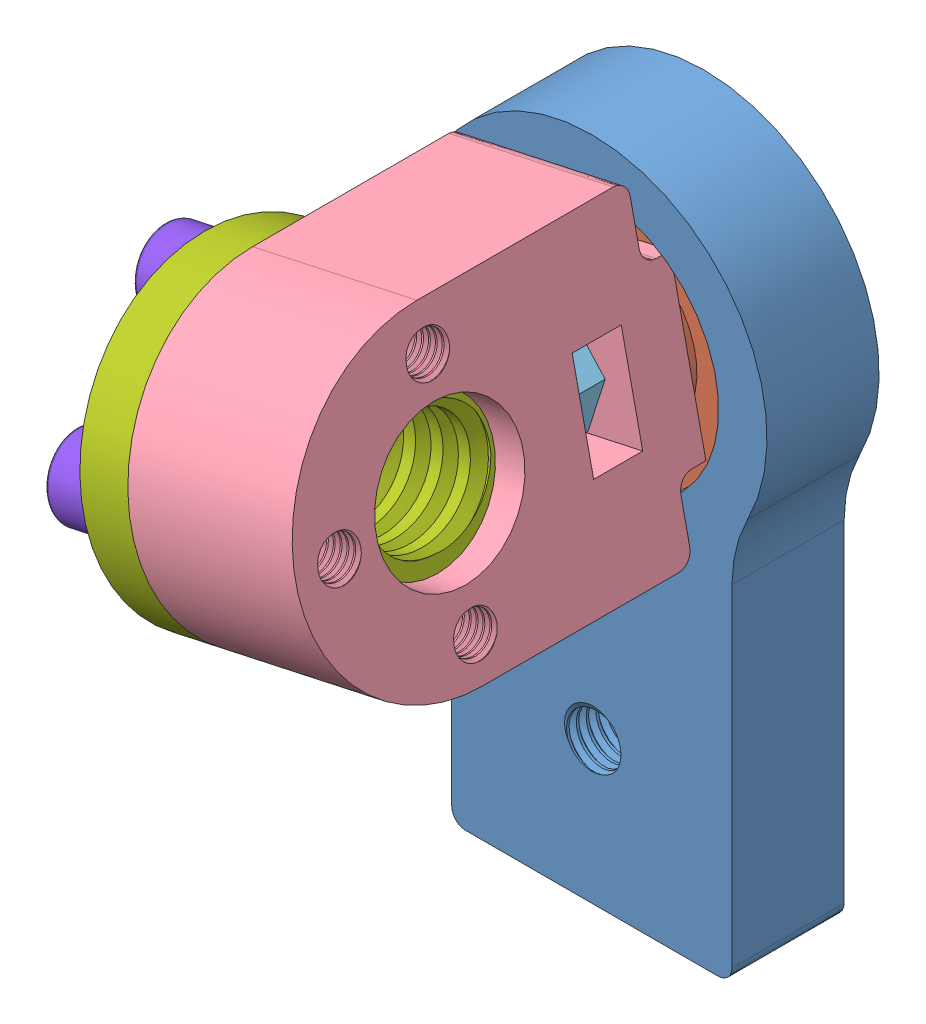
SolidWorks assembly ASM_poignee, configuration Défaut. Lengths in mm.
Overall size (28.85 49.13 41.76).
10 component instances, 8 part files, 25 mates.
Components (placement in the parent):
- fix_poignee_2-1: fix_poignee_2 [Défaut] at (-14.1041 -22.9722 47.5) size (25 47.5 8.25)
- roulement-1: roulement [Défaut] at (-14.1041 12.0278 51) x (0 0 1) z (0.937826 0.347107 0) size (7 22 22)
- rondelle_2-2: rondelle_2 [Défaut] at (-14.1041 12.0278 45.5) x (-0.1266 0.991954 0) z (0 0 -1) size (12.2 12.2 12)
- fix_ecrou_2-2: fix_ecrou_2 [Défaut] at (-8.2412 13.3032 56.5) x (0.212572 -0.977145 0) z (-0.977145 -0.212572 0) size (22 28 12.23)
- ecrou_M4-1: ecrou_M4 [Défaut] at (-14.1041 12.0278 58.5) x (0.672666 -0.739946 0) z (0 0 1) size (8.08 7 3.43)
- M4_16-1: M4_16 [Défaut] at (-14.1041 12.0278 41.5) x (-0.952519 0.30448 0) z (0.30448 0.952519 0) size (7 20.06 7)
- ecrou_cuivre-1: ecrou_cuivre [Défaut] at (-24.8527 9.6895 71.5) x (0.212572 -0.977145 0) z (0 0 1) size (22 16.12 22)
- M3_10-1: M3_10 [Défaut] at (-26.3184 9.3706 79.5) x (0.184093 -0.846233 -0.5) z (0.106286 -0.488573 0.866025) size (5.5 13 5.5)
- M3_10-2: M3_10 [Défaut] at (-28.019 17.1878 71.5) x (0.184093 -0.846233 -0.5) z (0.106286 -0.488573 0.866025) size (5.5 13 5.5)
- M3_10-3: M3_10 [Défaut] at (-24.6178 1.5535 71.5) x (0.184093 -0.846233 -0.5) z (0.106286 -0.488573 0.866025) size (5.5 13 5.5)
Mates (geometry in assembly coordinates):
- Coaxiale1: concentric anti-aligned: cylinder of fix_poignee_2-1 through (-14.1041 12.0278 54.5) axis (0 0 -1) radius 11.05; cylinder of roulement-1 through (-14.1041 12.0278 51) axis (0 0 1) radius 11
- Coïncidente1: coincident anti-aligned: plane of fix_poignee_2-1 through (-14.1041 12.0278 54.5) normal (0 0 -1); plane of roulement-1 through (-10.4594 2.1806 54.5) normal (0 0 1)
- Coaxiale4: concentric aligned: cylinder of roulement-1 through (-14.1041 12.0278 51) axis (0 0 1) radius 4; cylinder of rondelle_2-2 through (-14.1041 12.0278 53.0974) axis (0 0 1) radius 4.1
- Coïncidente5: coincident anti-aligned: plane of roulement-1 through (-12.5421 7.8076 47.5) normal (0 0 -1); plane of rondelle_2-2 through (-13.3318 5.9769 47.5) normal (0 0 1)
- Coaxiale5: concentric anti-aligned: cylinder of rondelle_2-2 through (-14.1041 12.0278 53.0974) axis (0 0 1) radius 4.1; cylinder of fix_ecrou_2-2 through (-14.1041 12.0278 63.5) axis (0 0 -1) radius 2.5
- Coïncidente6: coincident anti-aligned: plane of rondelle_2-2 through (-11.5953 15.2706 57.5) normal (0.790937 -0.611898 0); plane of fix_ecrou_2-2 through (-11.5035 15.3893 65.6544) normal (-0.790937 0.611898 0)
- Coïncidente7: coincident anti-aligned: plane of roulement-1 through (-12.0214 6.4008 54.5) normal (0 0 1); plane of fix_ecrou_2-2 through (-21.2424 16.6152 54.5) normal (0 0 -1)
- Coaxiale6: concentric aligned: cylinder of fix_ecrou_2-2 through (-14.1041 12.0278 63.5) axis (0 0 -1) radius 2.5; cone of ecrou_M4-1 through (-14.1041 12.0278 61.2) axis (0 0 -1)
- Coïncidente8: coincident anti-aligned: plane of fix_ecrou_2-2 through (-20.7322 14.2701 58.5) normal (0 0 1); plane of ecrou_M4-1 through (-14.1041 12.0278 58.5) normal (0 0 -1)
- Parallèle1: parallel anti-aligned: plane of fix_ecrou_2-2 through (-19.2017 7.2346 62) normal (-0.212572 0.977145 0); plane of ecrou_M4-1 through (-15.3346 8.1782 61.7) normal (0.212572 -0.977145 0)
- Coaxiale7: concentric aligned: cylinder of rondelle_2-2 through (-14.1041 12.0278 53.0974) axis (0 0 1) radius 2.5; cylinder of M4_16-1 through (-14.1041 12.0278 61.5) axis (0 0 1) radius 3.5
- Coïncidente10: coincident anti-aligned: plane of rondelle_2-2 through (-13.7876 9.5479 45.5) normal (0 0 -1); plane of M4_16-1 through (-10.7703 10.9621 45.5) normal (0 0 1)
- Parallèle3: parallel aligned: plane of fix_ecrou_2-2 through (-8.2412 13.3032 71.5) normal (0.977145 0.212572 0); plane of M4_16-1 through (-15.3857 10.8627 43.5) normal (0.977145 0.212572 0)
- Coaxiale8: concentric aligned: cylinder of fix_ecrou_2-2 through (-19.9669 10.7524 71.5) axis (0.977145 0.212572 0) radius 5.25; cylinder of ecrou_cuivre-1 through (-24.8527 9.6895 71.5) axis (0.977145 0.212572 0) radius 5.1
- Coaxiale9: concentric aligned: cylinder of ecrou_cuivre-1 through (-24.8527 9.6895 79.5) axis (0.977145 0.212572 0) radius 1.75; cylinder of M3_10-1 through (-13.6155 12.1341 79.5) axis (0.977145 0.212572 0) radius 2.75
- Coïncidente12: coincident anti-aligned: plane of ecrou_cuivre-1 through (-24.4711 14.9918 71.5) normal (-0.977145 -0.212572 0); plane of M3_10-1 through (-23.8932 12.3355 80.875) normal (0.977145 0.212572 0)
- Parallèle4: parallel aligned: plane of fix_ecrou_2-2 through (-22.3052 21.501 71.5) normal (-0.212572 0.977145 0); plane of M3_10-1 through (-24.0984 8.5744 78.7783) normal (-0.212572 0.977145 0)
- Coïncidente14: coincident anti-aligned: plane of ecrou_cuivre-1 through (-24.4711 14.9918 71.5) normal (-0.977145 -0.212572 0); plane of M3_10-2 through (-25.5938 20.1527 72.875) normal (0.977145 0.212572 0)
- Parallèle5: parallel aligned: plane of fix_ecrou_2-2 through (-22.3052 21.501 71.5) normal (-0.212572 0.977145 0); plane of M3_10-2 through (-25.799 16.3915 70.7783) normal (-0.212572 0.977145 0)
- Coaxiale10: concentric aligned: cylinder of ecrou_cuivre-1 through (-26.5532 17.5067 71.5) axis (0.977145 0.212572 0) radius 1.75; cylinder of M3_10-2 through (-15.3161 19.9512 71.5) axis (0.977145 0.212572 0) radius 2.75
- Coïncidente15: coincident anti-aligned: plane of ecrou_cuivre-1 through (-24.4711 14.9918 71.5) normal (-0.977145 -0.212572 0); plane of M3_10-3 through (-22.1926 4.5183 72.875) normal (0.977145 0.212572 0)
- Parallèle6: parallel aligned: plane of fix_ecrou_2-2 through (-22.3052 21.501 71.5) normal (-0.212572 0.977145 0); plane of M3_10-3 through (-22.3978 0.7572 70.7783) normal (-0.212572 0.977145 0)
- Coaxiale11: concentric aligned: cylinder of ecrou_cuivre-1 through (-23.1521 1.8723 71.5) axis (0.977145 0.212572 0) radius 1.75; cylinder of M3_10-3 through (-11.9149 4.3169 71.5) axis (0.977145 0.212572 0) radius 2.75
- Coaxiale13: concentric aligned: cone of fix_ecrou_2-2 through (-19.4784 10.8586 79.5) axis (0.977145 0.212572 0); circle of ecrou_cuivre-1
- Coïncidente19: coincident anti-aligned: plane of fix_ecrou_2-2 through (-19.9669 10.7524 71.5) normal (-0.977145 -0.212572 0); plane of ecrou_cuivre-1 through (-22.3052 21.501 71.5) normal (0.977145 0.212572 0)
